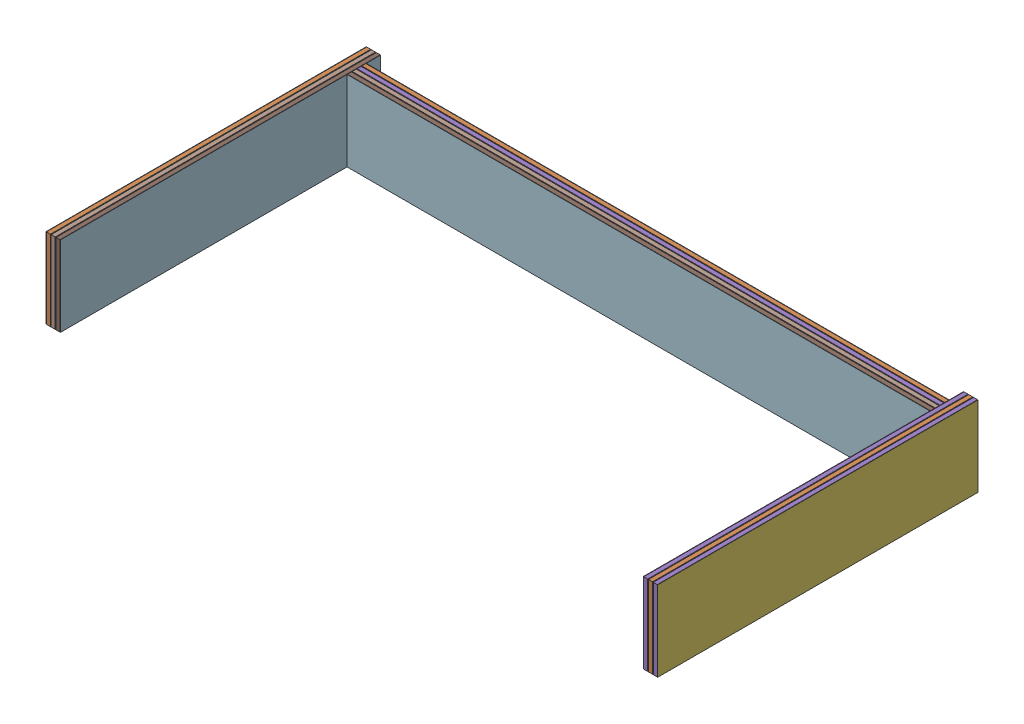
SolidWorks assembly Hip Part Assembly, configuration Default. Lengths in mm.
Overall size (382 50 200).
10 component instances, 3 part files, 28 mates.
Components (placement in the parent):
- Hip Part Layer-1: Hip Part Layer [Default] at (615.4137 849.4079 1306.501) size (376 50 3)
- Hip Part Layer-2: Hip Part Layer [Default] at (615.4137 849.4079 1309.501) size (376 50 3)
- Hip Part Layer-3: Hip Part Layer [Default] at (615.4137 849.4079 1312.501) size (376 50 3)
- Hip Part Layer-4: Hip Part Layer [Default] at (615.4137 849.4079 1315.501) size (376 50 3)
- Hip Part 2 Layer 3rd Layer-1: Hip Part 2 Layer 3rd Layer [Default] at (427.1637 849.4079 1394.751) size (3 50 200)
- Hip Part 2 Layer 3rd Layer-2: Hip Part 2 Layer 3rd Layer [Default] at (806.1637 849.4079 1394.751) size (3 50 200)
- Hip Part 2 Layer 1st and 2nd Layer-1: Hip Part 2 Layer 1st and 2nd Layer [Default] at (430.1637 849.4079 1394.751) size (3 50 200)
- Hip Part 2 Layer 1st and 2nd Layer-2: Hip Part 2 Layer 1st and 2nd Layer [Default] at (433.1637 849.4079 1394.751) size (3 50 200)
- Hip Part 2 Layer 1st and 2nd Layer-3: Hip Part 2 Layer 1st and 2nd Layer [Default] at (803.1637 849.4079 1394.751) size (3 50 200)
- Hip Part 2 Layer 1st and 2nd Layer-4: Hip Part 2 Layer 1st and 2nd Layer [Default] at (800.1637 849.4079 1394.751) size (3 50 200)
Mates (geometry in assembly coordinates):
- Coincident1: coincident anti-aligned: plane of Hip Part Layer-1 through (615.4137 849.4079 1306.751) normal (0 0 1); plane of Hip Part Layer-2 through (615.4137 849.4079 1306.751) normal (0 0 -1)
- Coincident2: coincident aligned: plane of Hip Part Layer-1 through (433.4137 874.4079 1306.751) normal (0 1 0); plane of Hip Part Layer-2 through (433.4137 874.4079 1306.751) normal (0 1 0)
- Coincident3: coincident aligned: plane of Hip Part Layer-1 through (803.4137 865.4079 1306.751) normal (1 0 0); plane of Hip Part Layer-2 through (803.4137 865.4079 1306.751) normal (1 0 0)
- Coincident4: coincident anti-aligned: plane of Hip Part Layer-2 through (615.4137 849.4079 1309.751) normal (0 0 1); plane of Hip Part Layer-3 through (615.4137 849.4079 1309.751) normal (0 0 -1)
- Coincident5: coincident aligned: line of Hip Part Layer-2 through (797.4137 865.4079 1307.001) axis (0 0 1); line of Hip Part Layer-3 through (797.4137 865.4079 1309.751) axis (0 0 1)
- Coincident6: coincident anti-aligned: plane of Hip Part Layer-3 through (615.4137 849.4079 1312.751) normal (0 0 1); plane of Hip Part Layer-4 through (615.4137 849.4079 1312.751) normal (0 0 -1)
- Coincident7: coincident anti-aligned: line of Hip Part Layer-3 through (797.4137 865.4079 1312.751) axis (0 0 -1); line of Hip Part Layer-4 through (797.4137 865.4079 1312.751) axis (0 0 1)
- Coincident8: coincident aligned: plane of Hip Part Layer-2 through (433.4137 874.4079 1309.751) normal (0 1 0); plane of Hip Part Layer-3 through (433.4137 874.4079 1309.751) normal (0 1 0)
- Coincident9: coincident aligned: plane of Hip Part Layer-3 through (433.4137 874.4079 1312.751) normal (0 1 0); plane of Hip Part Layer-4 through (433.4137 874.4079 1312.751) normal (0 1 0)
- Coincident10: coincident anti-aligned: plane of Hip Part 2 Layer 1st and 2nd Layer-1 through (430.4137 849.4079 1328.6005) normal (1 0 0); plane of Hip Part 2 Layer 1st and 2nd Layer-2 through (460.2791 846.4732 1392.3175) normal (-1 0 0)
- Coincident11: coincident anti-aligned: plane of Hip Part 2 Layer 3rd Layer-1 through (427.4137 849.4079 1328.6005) normal (1 0 0); plane of Hip Part 2 Layer 1st and 2nd Layer-1 through (427.4137 849.4079 1328.6005) normal (-1 0 0)
- Coincident12: coincident aligned: plane of Hip Part 2 Layer 1st and 2nd Layer-1 through (430.4137 874.4079 1228.6005) normal (0 0 -1); plane of Hip Part 2 Layer 1st and 2nd Layer-2 through (460.2791 846.4732 1292.3175) normal (0 0 -1)
- Coincident13: coincident aligned: plane of Hip Part 2 Layer 3rd Layer-1 through (427.4137 874.4079 1228.6005) normal (0 0 -1); plane of Hip Part 2 Layer 1st and 2nd Layer-1 through (427.4137 849.4079 1228.6005) normal (0 0 -1)
- Coincident14: coincident aligned: plane of Hip Part 2 Layer 1st and 2nd Layer-1 through (430.4137 874.4079 1428.6005) normal (0 1 0); plane of Hip Part 2 Layer 1st and 2nd Layer-2 through (460.2791 871.4732 1392.3175) normal (0 1 0)
- Coincident15: coincident aligned: plane of Hip Part 2 Layer 3rd Layer-1 through (427.4137 874.4079 1428.6005) normal (0 1 0); plane of Hip Part 2 Layer 1st and 2nd Layer-1 through (427.4137 874.4079 1328.6005) normal (0 1 0)
- Coincident16: coincident anti-aligned: plane of Hip Part 2 Layer 3rd Layer-2 through (803.4137 849.4079 1394.751) normal (-1 0 0); plane of Hip Part 2 Layer 1st and 2nd Layer-3 through (803.4137 849.4079 1394.751) normal (1 0 0)
- Coincident17: coincident anti-aligned: plane of Hip Part 2 Layer 1st and 2nd Layer-3 through (800.4137 849.4079 1394.751) normal (-1 0 0); plane of Hip Part 2 Layer 1st and 2nd Layer-4 through (800.4137 849.4079 1394.751) normal (1 0 0)
- Coincident18: coincident aligned: plane of Hip Part 2 Layer 3rd Layer-2 through (803.4137 849.4079 1294.751) normal (0 0 -1); plane of Hip Part 2 Layer 1st and 2nd Layer-3 through (803.4137 874.4079 1294.751) normal (0 0 -1)
- Coincident19: coincident aligned: plane of Hip Part 2 Layer 1st and 2nd Layer-3 through (800.4137 849.4079 1294.751) normal (0 0 -1); plane of Hip Part 2 Layer 1st and 2nd Layer-4 through (800.4137 874.4079 1294.751) normal (0 0 -1)
- Coincident20: coincident aligned: plane of Hip Part 2 Layer 1st and 2nd Layer-3 through (800.4137 874.4079 1394.751) normal (0 1 0); plane of Hip Part 2 Layer 1st and 2nd Layer-4 through (800.4137 874.4079 1494.751) normal (0 1 0)
- Coincident21: coincident aligned: plane of Hip Part 2 Layer 3rd Layer-2 through (803.4137 874.4079 1394.751) normal (0 1 0); plane of Hip Part 2 Layer 1st and 2nd Layer-3 through (803.4137 874.4079 1494.751) normal (0 1 0)
- Coincident22: coincident anti-aligned: plane of Hip Part Layer-2 through (803.4137 849.4079 1307.001) normal (1 0 0); plane of Hip Part 2 Layer 3rd Layer-2 through (803.4137 849.4079 1394.751) normal (-1 0 0)
- Coincident23: coincident anti-aligned: plane of Hip Part Layer-3 through (797.4137 849.4079 1310.001) normal (1 0 0); plane of Hip Part 2 Layer 1st and 2nd Layer-4 through (797.4137 849.4079 1394.751) normal (-1 0 0)
- Coincident24: coincident anti-aligned: plane of Hip Part Layer-3 through (615.4137 865.4079 1310.001) normal (0 1 0); plane of Hip Part 2 Layer 1st and 2nd Layer-4 through (797.6637 865.4079 1394.751) normal (0 -1 0)
- Coincident25: coincident anti-aligned: plane of Hip Part Layer-1 through (615.4137 849.4079 1303.751) normal (0 0 -1); plane of Hip Part 2 Layer 1st and 2nd Layer-4 through (797.6637 849.4079 1303.751) normal (0 0 1)
- Coincident26: coincident anti-aligned: plane of Hip Part Layer-3 through (427.4137 849.4079 1310.001) normal (-1 0 0); plane of Hip Part 2 Layer 3rd Layer-1 through (427.4137 849.4079 1394.751) normal (1 0 0)
- Coincident27: coincident: line of Hip Part Layer-2 through (433.4137 865.4079 1309.501) axis (-1 0 0); plane of Hip Part 2 Layer 1st and 2nd Layer-2 through (430.6637 865.4079 1394.751) normal (0 -1 0)
- Coincident28: coincident anti-aligned: plane of Hip Part Layer-1 through (615.4137 849.4079 1303.751) normal (0 0 -1); plane of Hip Part 2 Layer 1st and 2nd Layer-2 through (430.6637 849.4079 1303.751) normal (0 0 1)
